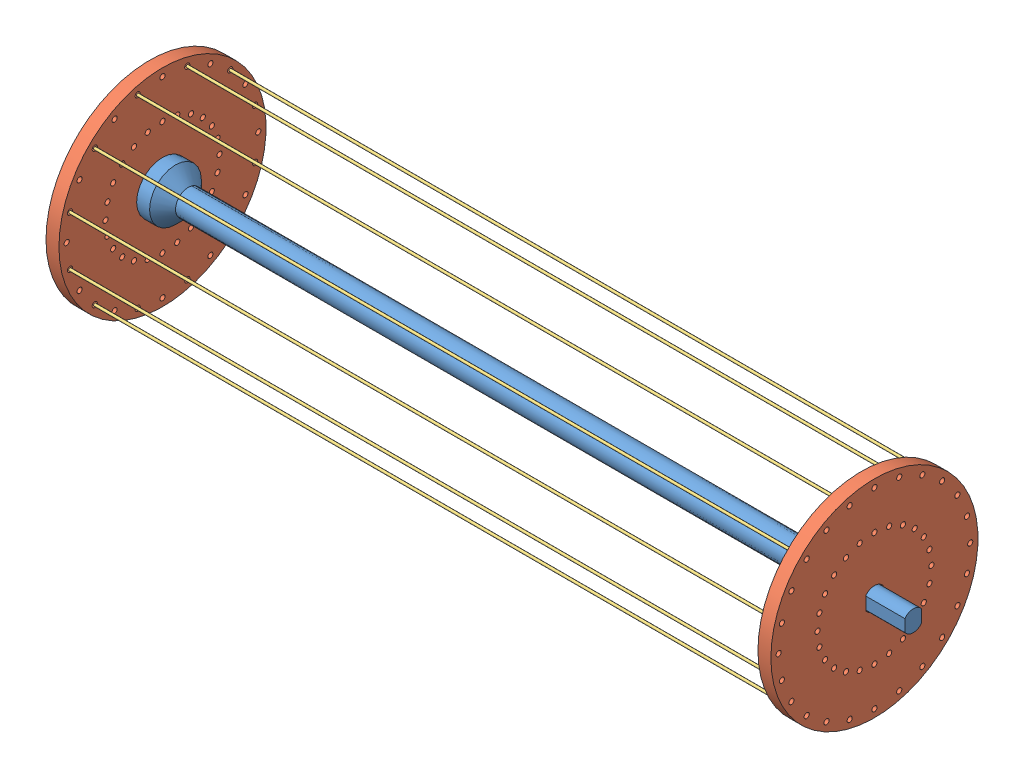
SolidWorks assembly Brush Assembly, configuration Default. Lengths in mm.
Overall size (315 80 80).
15 component instances, 3 part files, 11 mates.
Components (placement in the parent):
- Brush Axle-2: Brush Axle [Default] at origin size (315 20 20)
- Brush Wheel-1: Brush Wheel [Default] at (140 0 0) x (0 0 -1) z (-1 0 0) size (80 80 5)
- Brush Wheel-2: Brush Wheel [Default] at (-140 0 0) x (0 0 -1) z (1 0 0) size (80 80 5)
- String-1: String [Default] at (135 35.7393 -9.5763) x (0 -0.999566 -0.029459) z (-1 0 0) size (1 1 270)
- String-2: String [Default] at (135 35.7393 9.5763) x (0 -0.85092 -0.525295) z (-1 0 0) size (1 1 270)
- String-3: String [Default] at (135 26.163 26.163) x (0 -0.474271 -0.880379) z (-1 0 0) size (1 1 270)
- String-4: String [Default] at (135 9.5763 35.7393) x (0 0.029459 -0.999566) z (-1 0 0) size (1 1 270)
- String-5: String [Default] at (135 -9.5763 35.7393) x (0 0.525295 -0.85092) z (-1 0 0) size (1 1 270)
- String-6: String [Default] at (135 -26.163 26.163) x (0 0.880379 -0.474271) z (-1 0 0) size (1 1 270)
- String-7: String [Default] at (135 -35.7393 9.5763) x (0 0.999566 0.029459) z (-1 0 0) size (1 1 270)
- String-8: String [Default] at (135 -35.7393 -9.5763) x (0 0.85092 0.525295) z (-1 0 0) size (1 1 270)
- String-9: String [Default] at (135 -26.163 -26.163) x (0 0.474271 0.880379) z (-1 0 0) size (1 1 270)
- String-10: String [Default] at (135 -9.5763 -35.7393) x (0 -0.029459 0.999566) z (-1 0 0) size (1 1 270)
- String-11: String [Default] at (135 9.5763 -35.7393) x (0 -0.525295 0.85092) z (-1 0 0) size (1 1 270)
- String-12: String [Default] at (135 26.163 -26.163) x (0 -0.880379 0.474271) z (-1 0 0) size (1 1 270)
Mates (geometry in assembly coordinates):
- Coincident1: coincident aligned: plane of Brush Axle-2 through (0 0 0) normal (0 0 1); plane of assembly through (0 0 0) normal (0 0 1)
- Coincident2: coincident aligned: plane of Brush Axle-2 through (0 0 0) normal (0 1 0); plane of assembly through (0 0 0) normal (0 1 0)
- Coincident3: coincident aligned: plane of Brush Axle-2 through (0 0 0) normal (1 0 0); plane of assembly through (0 0 0) normal (1 0 0)
- Concentric1: concentric anti-aligned: circle of Brush Axle-2; cylinder of Brush Wheel-1 through (135 0 0) axis (1 0 0) radius 4.25
- Coincident6: coincident anti-aligned: plane of Brush Axle-2 through (135 10 3.25) normal (0 0 1); plane of Brush Wheel-1 through (135 -2.7386 3.25) normal (0 0 -1)
- Coincident7: coincident anti-aligned: plane of Brush Axle-2 through (135 10 0) normal (1 0 0); plane of Brush Wheel-1 through (135 0 0) normal (-1 0 0)
- Concentric2: concentric anti-aligned: circle of Brush Axle-2; cylinder of Brush Wheel-2 through (-135 0 0) axis (-1 0 0) radius 4.25
- Coincident8: coincident anti-aligned: plane of Brush Axle-2 through (-160 10 3.25) normal (0 0 1); plane of Brush Wheel-2 through (-135 2.7386 3.25) normal (0 0 -1)
- Coincident9: coincident anti-aligned: plane of Brush Axle-2 through (-135 10 0) normal (-1 0 0); plane of Brush Wheel-2 through (-135 0 0) normal (1 0 0)
- Concentric3: concentric anti-aligned: circle of Brush Wheel-2; circle of String-1
- Coincident11: coincident anti-aligned: plane of Brush Wheel-2 through (-135 0 0) normal (1 0 0); circle of String-1
